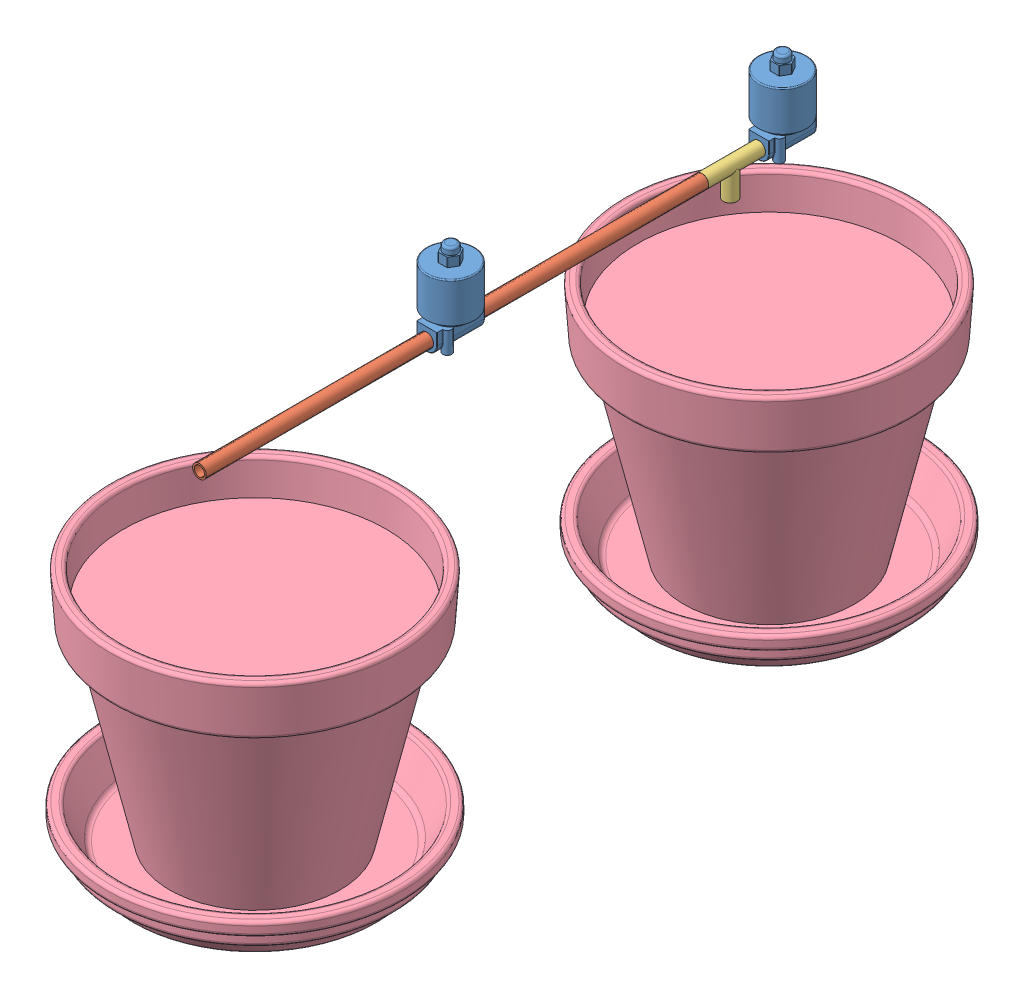
SolidWorks assembly Ensamble, configuration Predeterminado. Lengths in mm.
Overall size (268.53 364 703.78).
7 component instances, 4 part files, 12 mates.
Components (placement in the parent):
- Solenoid Valve-1: Solenoid Valve [Default] at (-5.9776 -30.3038 73.1364) size (42 73.14 42.51)
- Tubo 30-1: Tubo 30 [Predeterminado] at (-5.9776 -30.8038 173.1364) x (-0.566717 -0.823913 0) z (0 0 1) size (12 12 200)
- Tubo 30-2: Tubo 30 [Predeterminado] at (-5.9776 -30.8038 -68.8636) x (0.918154 0.396224 0) z (0 0 1) size (12 12 200)
- tubo T-1: tubo T [Predeterminado] at (-5.9776 -30.8038 -193.8636) x (-1 0 0) z (0 0 1) size (12 31 50)
- Solenoid Valve-2: Solenoid Valve [Default] at (-5.9776 -30.3038 -218.8636) size (42 73.14 42.51)
- Plantpot_Terracotta_25cm.step-1: Plantpot_Terracotta_25cm.step [Predeterminado] at (-459.0114 843.5429 394.4734) x (-1 0 0) z (0 1 0) size (260 260 220)
- Plantpot_Terracotta_25cm.step-2: Plantpot_Terracotta_25cm.step [Predeterminado] at (-135.6485 843.5429 -672.4752) x (0 0 -1) z (0 1 0) size (260 260 220)
Mates (geometry in assembly coordinates):
- Concéntrica1: concentric aligned: circle of Solenoid Valve-1; circle of Tubo 30-1
- Coincidente3: coincident anti-aligned: plane of Solenoid Valve-1 through (-5.9776 -30.3038 73.1364) normal (0 0 1); plane of Tubo 30-1 through (-5.9776 -30.8038 73.1364) normal (0 0 -1)
- Concéntrica2: concentric aligned: circle of Tubo 30-1; circle of Tubo 30-2
- Coincidente5: coincident anti-aligned: plane of Solenoid Valve-1 through (-5.9776 -30.3038 31.1364) normal (0 0 -1); plane of Tubo 30-2 through (-5.9776 -30.8038 31.1364) normal (0 0 1)
- Concéntrica3: concentric aligned: circle of Tubo 30-2; circle of tubo T-1
- Coincidente8: coincident anti-aligned: plane of Tubo 30-2 through (-5.9776 -30.8038 -168.8636) normal (0 0 -1); plane of tubo T-1 through (-5.9776 -30.8038 -168.8636) normal (0 0 1)
- Ángulo1: planar angle = 3.141593 rad aligned: plane of tubo T-1 through (-5.9776 -55.8038 -193.8636) normal (0 -1 0); plane of Solenoid Valve-1 through (3.0224 -20.8038 31.1364) normal (0 1 0)
- Concéntrica4: concentric aligned: circle of tubo T-1; circle of Solenoid Valve-2
- Coincidente10: coincident anti-aligned: plane of tubo T-1 through (-5.9776 -30.8038 -218.8636) normal (0 0 -1); plane of Solenoid Valve-2 through (-5.9776 -30.3038 -218.8636) normal (0 0 1)
- Coincidente11: coincident aligned: plane of Solenoid Valve-1 through (-5.9776 19.1962 52.1364) normal (0 1 0); plane of Solenoid Valve-2 through (-5.9776 19.1962 -239.8636) normal (0 1 0)
- Coincidente13: coincident aligned: plane of Plantpot_Terracotta_25cm.step-1 through (9.9886 -330.8038 187.1229) normal (0 -1 0); plane of Plantpot_Terracotta_25cm.step-2 through (71.702 -330.8038 -203.4752) normal (0 -1 0)
- Distancia1: distance = 350 mm anti-aligned: plane of Plantpot_Terracotta_25cm.step-2 through (71.702 -330.8038 -203.4752) normal (0 -1 0); plane of Solenoid Valve-2 through (-5.9776 19.1962 -239.8636) normal (0 1 0)
